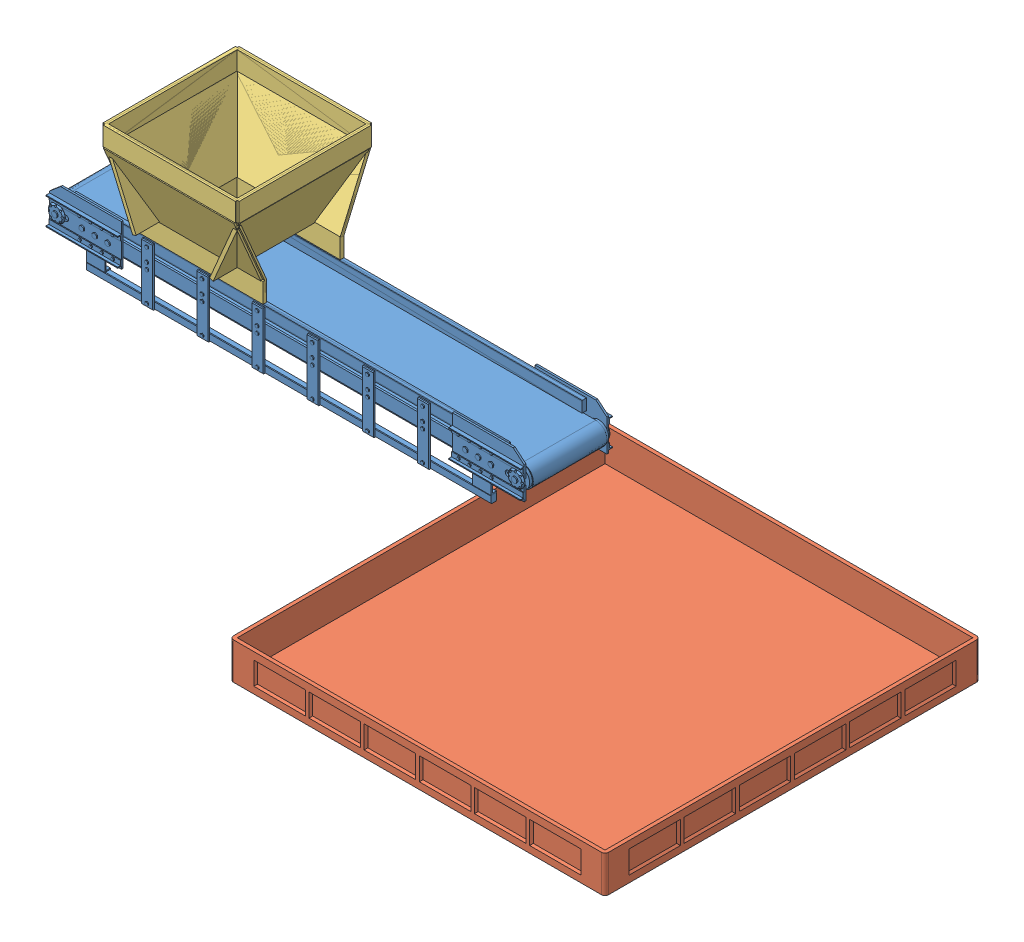
SolidWorks assembly assembly_conveyor, configuration Default. Lengths in mm.
Overall size (3830 1700 2040).
3 component instances, 3 part files, 9 mates.
Components (placement in the parent):
- conveyor^assembly_conveyor-1: conveyor^assembly_conveyor [Default] at (-1500 1000 0) size (2620 335 500) (virtual)
- floor_box^assembly_conveyor-1: floor_box^assembly_conveyor [Default] x (-1 0 0) z (0 1 0) size (2040 2040 280) (virtual)
- hopper^assembly_conveyor-1: hopper^assembly_conveyor [Default] at (-2000 1020 0) size (740 600 740) (virtual)
Mates (geometry in assembly coordinates):
- Distanza1: distance = 1000 mm aligned: plane of conveyor^assembly_conveyor-1 through (-2750 1000 -200) normal (0 1 0); plane of assembly through (0 0 0) normal (0 1 0)
- Distanza2: distance = 1500 mm aligned: plane of conveyor^assembly_conveyor-1 through (-1500 1000 0) normal (1 0 0); plane of assembly through (0 0 0) normal (1 0 0)
- Coincidente3: coincident aligned: plane of conveyor^assembly_conveyor-1 through (-1500 1000 0) normal (0 0 1); plane of assembly through (0 0 0) normal (0 0 1)
- Coincidente4: coincident aligned: plane of floor_box^assembly_conveyor-1; plane of assembly through (0 0 0) normal (0 0 1)
- Coincidente5: coincident anti-aligned: plane of floor_box^assembly_conveyor-1 through (1020 0 -1020) normal (0 -1 0); plane of assembly through (0 0 0) normal (0 1 0)
- Coincidente6: coincident anti-aligned: plane of floor_box^assembly_conveyor-1; plane of assembly through (0 0 0) normal (1 0 0)
- Coincidente8: coincident: plane of conveyor^assembly_conveyor-1 through (-1500 1000 0) normal (0 0 1); plane of hopper^assembly_conveyor-1 through (-2000 1020 0) normal (0 0 1)
- Distanza3: distance = 20 mm: plane of hopper^assembly_conveyor-1 through (-2000 1020 0) normal (0 1 0); plane of conveyor^assembly_conveyor-1 through (-1500 1000 0) normal (0 1 0)
- Distanza4: distance = 500 mm aligned: plane of hopper^assembly_conveyor-1 through (-2000 1020 0) normal (1 0 0); plane of conveyor^assembly_conveyor-1 through (-1500 1000 0) normal (1 0 0)
